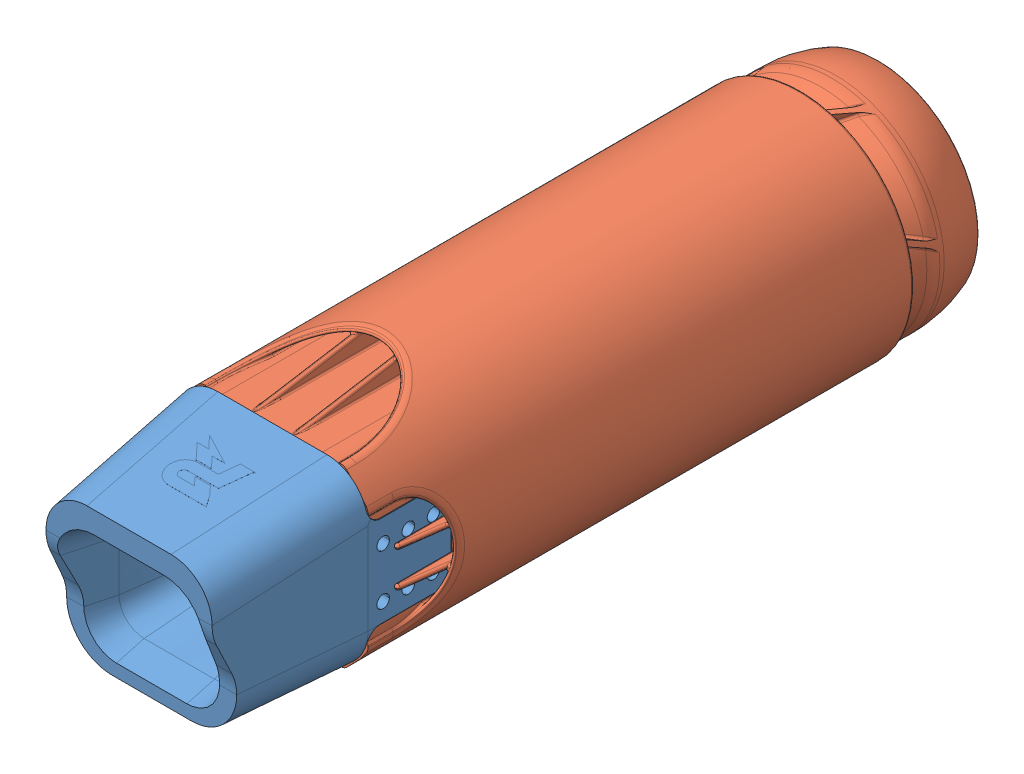
SolidWorks assembly 装配体1, configuration 默认. Lengths in mm.
Overall size (45.67 48.63 150.2).
2 component instances, 2 part files, 12 mates.
Components (placement in the parent):
- RM2020 飞镖触发装置3D模型-1: RM2020 飞镖触发装置3D模型 [Default] at (0 19.35 48.5) x (-1 0 0) z (0 1 0) size (38.05 93.7 35.39)
- 飞镖外形XIV_3-1: 飞镖外形XIV_3 [默认] x (-1 0 0) z (0 0 -1) size (45.67 48.63 120.55)
Mates (geometry in assembly coordinates):
- 重合5: coincident anti-aligned: plane of RM2020 飞镖触发装置3D模型-1 through (0 19.35 48.5) normal (-1 0 0)
- 同心1: concentric aligned: cylinder of RM2020 飞镖触发装置3D模型-1 through (-18.9939 4.9655 57) axis (-1 0 0) radius 1.25; cylinder of 飞镖外形XIV_3-1 through (22.8359 4.9655 57) axis (-1 0 0) radius 1.05
- 同心2: concentric aligned: cylinder of RM2020 飞镖触发装置3D模型-1 through (-18.9939 -5.0345 57) axis (-1 0 0) radius 1.25; cylinder of 飞镖外形XIV_3-1 through (22.8359 -5.0345 57) axis (-1 0 0) radius 1.05
- 重合14: coincident anti-aligned: plane of 飞镖外形XIV_3-1 through (0 0 0) normal (-1 0 0)
- 重合15: coincident aligned: plane of 飞镖外形XIV_3-1 through (0 0 0) normal (0 1 0)
- 重合16: coincident anti-aligned: plane of 飞镖外形XIV_3-1 through (0 0 0) normal (0 0 -1)
- 相切1: tangent anti-aligned: cylinder of 飞镖外形XIV_3-1 through (0 0 -60) axis (0 0 1) radius 22.5; sphere of M6×12-1
- 重合17: coincident aligned: plane of M6×12-1 through (0 28.5 52.9833) normal (1 0 0)
- 平行1: parallel aligned: plane of M6×12-1 through (-2.95 34.5 52.9833) normal (0 1 0)
- 相切2: tangent anti-aligned: cylinder of 飞镖外形XIV_3-1 through (0 0 -60) axis (0 0 1) radius 22.5; sphere of M8×14-1
- 重合18: coincident aligned: plane of M8×14-1 through (0 29.5 37.1731) normal (1 0 0)
- 平行2: parallel aligned: plane of M8×14-1 through (-3.9 36.5 37.1731) normal (0 1 0)
